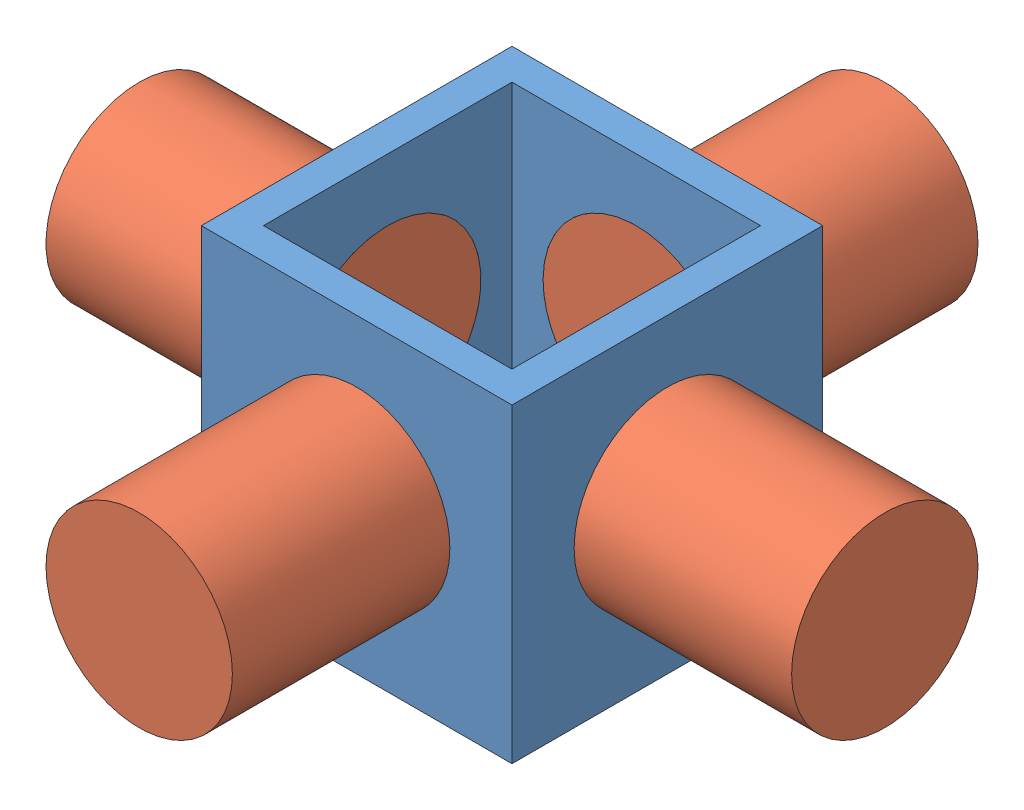
SolidWorks assembly Assem2, configuration Default. Lengths in mm.
Overall size (140.9 50 140.38).
5 component instances, 2 part files, 12 mates.
Components (placement in the parent):
- Yoke-1: Yoke [Default] at (-60 0 -25) x (0 0 -1) z (1 0 0) size (50 50 50)
- Pin-1: Pin [Default] at origin size (40 30 30)
- Pin-2: Pin [Default] at (-60 0 -60) x (0 0 -1) z (1 0 0) size (40 30 30)
- Pin-3: Pin [Default] at (-60 0 20) x (0 0 -1) z (1 0 0) size (40 30 30)
- Pin-4: Pin [Default] at (-120 0 0) x (-1 0 0) z (0 -0.582353 -0.812936) size (40 30 30)
Mates (geometry in assembly coordinates):
- Concentric1: concentric anti-aligned: cylinder of Yoke-1 through (-35 0 0) axis (-1 0 0) radius 15; cylinder of Pin-1 through (-40 0 0) axis (1 0 0) radius 15
- Coincident1: coincident aligned: plane of Yoke-1 through (-40 -25 20) normal (-1 0 0); plane of Pin-1 through (-40 0 0) normal (-1 0 0)
- Concentric2: concentric aligned: cylinder of Yoke-1 through (-60 0 25) axis (0 0 -1) radius 15; cylinder of Pin-2 through (-60 0 -20) axis (0 0 -1) radius 15
- Coincident2: coincident aligned: plane of Yoke-1 through (-80 -25 -20) normal (0 0 1); plane of Pin-2 through (-60 0 -20) normal (0 0 1)
- Concentric3: concentric aligned: cylinder of Yoke-1 through (-60 0 25) axis (0 0 -1) radius 15; cylinder of Pin-3 through (-60 0 60) axis (0 0 -1) radius 15
- Coincident3: coincident aligned: plane of Yoke-1 through (-80 -25 20) normal (0 0 -1); plane of Pin-3 through (-60 0 20) normal (0 0 -1)
- Concentric4: concentric aligned: cylinder of Yoke-1 through (-35 0 0) axis (-1 0 0) radius 15; cylinder of Pin-4 through (-80 0 0) axis (-1 0 0) radius 15
- Coincident4: coincident aligned: plane of Yoke-1 through (-80 -25 20) normal (1 0 0); plane of Pin-4 through (-80 0 0) normal (1 0 0)
- Coincident8: coordinate: point of Pin-1
- Coincident9: coincident aligned: plane of Pin-1 through (0 0 0) normal (0 0 1)
- Coincident10: coincident: plane of assembly through (0 0 0) normal (0 1 0); plane of Pin-1 through (0 0 0) normal (0 1 0); plane of assembly
- Coincident11: coincident aligned: plane of Pin-1 through (0 0 0) normal (1 0 0)
